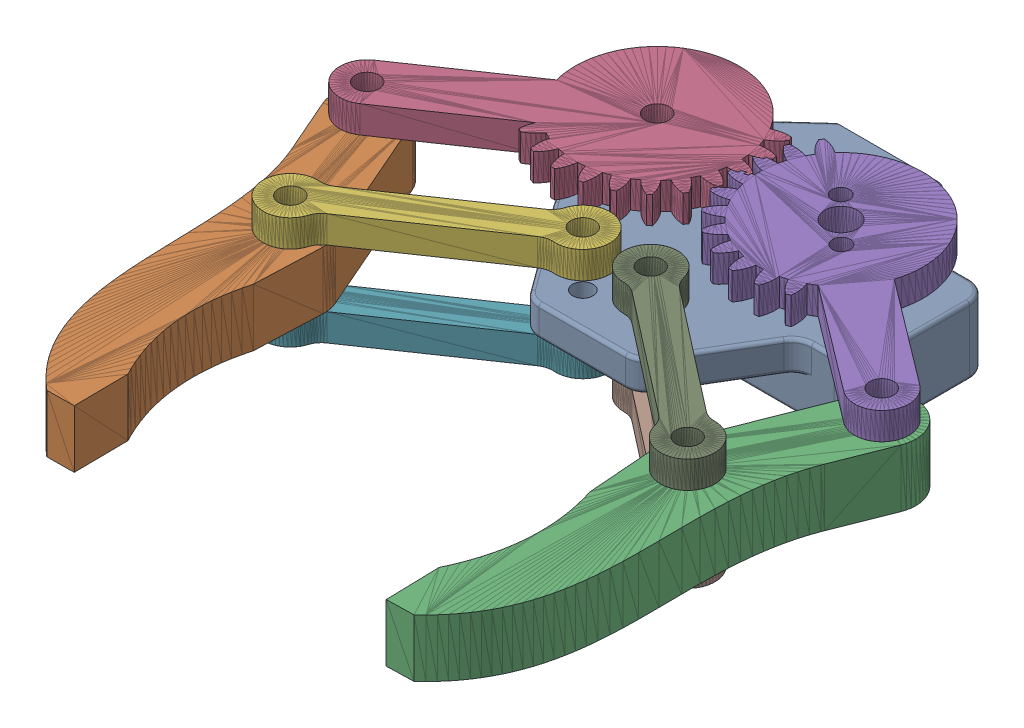
SolidWorks assembly gripper assembly, configuration Default. Lengths in mm.
Overall size (109.23 27.5 100.25).
9 component instances, 5 part files, 26 mates.
Components (placement in the parent):
- gripper links rotation mount-1: gripper links rotation mount [Default] at (-16.4104 7.7495 23.6568) size (44 19.5 45)
- Gripper 1-1: Gripper 1 [Default] at (-19.1031 16.2495 69.2093) x (0 -1 0) z (-0.400309 0 -0.91638) size (8.5 20.39 65.3)
- Gripper 1-2: Gripper 1 [Default] at (2.4006 7.7495 71.4396) x (0 1 0) z (0.366353 0 -0.930476) size (8.5 20.39 65.3)
- gear1-1: gear1 [Default] at (-2.2588 16.2495 2.4533) x (-0.825796 0 0.563969) z (-0.563969 0 -0.825796) size (49.28 4 26.62)
- gear2-1: gear2 [Default] at (18.9933 16.2495 33.1972) x (-0.712433 0 -0.70174) z (0.70174 0 -0.712433) size (49.02 4 26.63)
- grip link 1-1: grip link 1 [Default] at (-44.5567 16.2495 35.1162) x (0.825369 0 -0.564594) z (0.564594 0 0.825369) size (38.99 4 8)
- grip link 1-2: grip link 1 [Default] at (-44.5567 3.7495 35.1162) x (0.825369 0 -0.564594) z (0.564594 0 0.825369) size (38.99 4 8)
- grip link 1-5: grip link 1 [Default] at (21.7696 3.7495 43.2936) x (-0.789561 0 -0.613672) z (0.613672 0 -0.789561) size (38.99 4 8)
- grip link 1-6: grip link 1 [Default] at (21.7696 16.2495 43.2936) x (-0.789561 0 -0.613672) z (0.613672 0 -0.789561) size (38.99 4 8)
Mates (geometry in assembly coordinates):
- Coincident1: coincident aligned: line of Gripper 1-1 through (-38.9968 7.3245 36.1593) axis (0 1 0); line of grip link 1-1 through (-38.9968 16.0495 36.1593) axis (0 1 0)
- Coincident2: coincident aligned: line of Gripper 1-1 through (-38.9968 7.3245 36.1593) axis (0 1 0); line of grip link 1-2 through (-38.9968 3.5495 36.1593) axis (0 1 0)
- Coincident3: coincident anti-aligned: plane of Gripper 1-1 through (-19.1031 7.7495 69.2093) normal (0 -1 0); plane of grip link 1-2 through (-44.5567 7.7495 35.1162) normal (0 1 0)
- Coincident4: coincident anti-aligned: plane of Gripper 1-1 through (-19.1031 16.2495 69.2093) normal (0 1 0); plane of grip link 1-1 through (-44.5567 16.2495 35.1162) normal (0 -1 0)
- Coincident5: coincident aligned: line of gripper links rotation mount-1 through (-13.4104 12.2495 18.6568) axis (0 -1 0); line of grip link 1-1 through (-13.4104 20.4495 18.6568) axis (0 -1 0)
- Coincident6: coincident anti-aligned: line of gripper links rotation mount-1 through (-22.4104 12.2495 -1.3432) axis (0 -1 0); line of gear1-1 through (-22.4104 16.0495 -1.3432) axis (0 1 0)
- Coincident7: coincident anti-aligned: plane of Gripper 1-1 through (-19.1031 16.2495 69.2093) normal (0 1 0); plane of gear1-1 through (-2.2588 16.2495 2.4533) normal (0 -1 0)
- Coincident8: coincident aligned: line of Gripper 1-1 through (-47.8036 16.6745 15.9989) axis (0 -1 0); line of gear1-1 through (-47.8036 20.4495 15.9989) axis (0 -1 0)
- Coincident9: coincident anti-aligned: line of gripper links rotation mount-1 through (4.5896 -8.2255 -1.3432) axis (0 1 0); line of gear2-1 through (4.5896 20.4495 -1.3432) axis (0 -1 0)
- Coincident10: coincident aligned: line of Gripper 1-2 through (29.1258 7.3245 17.2102) axis (0 1 0); line of gear2-1 through (29.1258 16.0495 17.2102) axis (0 1 0)
- Coincident11: coincident anti-aligned: plane of Gripper 1-2 through (2.4006 16.2495 71.4396) normal (0 1 0); plane of gear2-1 through (18.9933 16.2495 33.1972) normal (0 -1 0)
- Coincident12: coincident aligned: line of Gripper 1-2 through (29.1258 7.3245 17.2102) axis (0 1 0); line of grip link 1-3 through (29.1258 3.5495 17.2102) axis (0 1 0)
- Coincident13: coincident anti-aligned: plane of Gripper 1-2 through (2.4006 7.7495 71.4396) normal (0 -1 0); plane of grip link 1-3 through (24.5645 7.7495 20.5561) normal (0 1 0)
- Coincident14: coincident anti-aligned: line of Gripper 1-2 through (21.066 16.6745 37.6807) axis (0 -1 0); line of grip link 1-5 through (21.066 3.5495 37.6807) axis (0 1 0)
- Coincident15: coincident anti-aligned: plane of Gripper 1-2 through (2.4006 7.7495 71.4396) normal (0 -1 0); plane of grip link 1-5 through (21.7696 7.7495 43.2936) normal (0 1 0)
- Coincident16: coincident anti-aligned: line of Gripper 1-2 through (21.066 16.6745 37.6807) axis (0 -1 0); line of grip link 1-6 through (21.066 16.0495 37.6807) axis (0 1 0)
- Coincident17: coincident anti-aligned: plane of Gripper 1-2 through (2.4006 16.2495 71.4396) normal (0 1 0); plane of grip link 1-6 through (21.7696 16.2495 43.2936) normal (0 -1 0)
- Coincident18: coincident anti-aligned: line of Gripper 1-1 through (-47.8036 16.6745 15.9989) axis (0 -1 0); line of grip link 1-4 through (-51.9622 3.5495 -9.8433) axis (0 1 0)
- Coincident19: coincident anti-aligned: plane of Gripper 1-1 through (-19.1031 7.7495 69.2093) normal (0 -1 0); plane of grip link 1-4 through (-54.2603 7.7495 -15.0123) normal (0 1 0)
- Coincident20: coincident aligned: line of gripper links rotation mount-1 through (-3.4104 12.2495 18.6568) axis (0 -1 0); line of grip link 1-6 through (-3.4104 20.4495 18.6568) axis (0 -1 0)
- Coincident21: coincident aligned: line of gripper links rotation mount-1 through (-3.4104 12.2495 18.6568) axis (0 -1 0); line of grip link 1-5 through (-3.4104 7.9495 18.6568) axis (0 -1 0)
- Coincident24: coincident aligned: line of gripper links rotation mount-1 through (-13.4104 12.2495 18.6568) axis (0 -1 0); line of grip link 1-2 through (-13.4104 7.9495 18.6568) axis (0 -1 0)
- Parallel3: parallel aligned: plane of gear1-1 through (-2.2588 20.2495 2.4533) normal (0 1 0); plane of gear2-1 through (18.9933 20.2495 33.1972) normal (0 1 0)
- Coincident27: coincident anti-aligned: plane of gripper links rotation mount-1 through (-16.4104 7.7495 23.6568) normal (0 -1 0); plane of grip link 1-2 through (-44.5567 7.7495 35.1162) normal (0 1 0)
- Coincident28: coincident anti-aligned: plane of gripper links rotation mount-1 through (-16.4104 7.7495 23.6568) normal (0 -1 0); plane of grip link 1-5 through (21.7696 7.7495 43.2936) normal (0 1 0)
- Parallel4: parallel aligned: line of gripper links rotation mount-1 through (-22.4104 12.2495 -1.3432) axis (0 -1 0); line of grip link 1-4 through (-23.0273 7.9495 1.2819) axis (0 -1 0)
